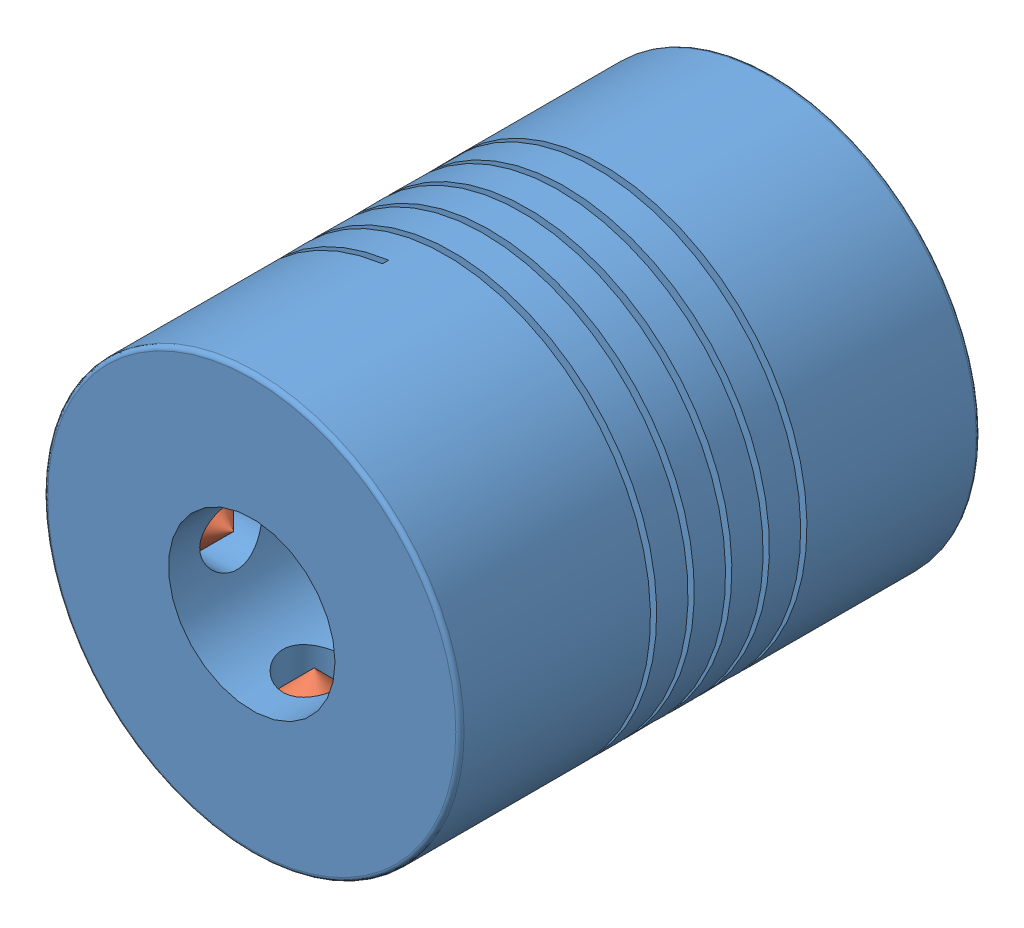
SolidWorks assembly Acople Flexible, configuration Predeterminado. Lengths in mm.
Overall size (20.77 20.77 25).
5 component instances, 2 part files, 4 mates.
Components (placement in the parent):
- Acople FlexibleSLDPRT-1: Acople FlexibleSLDPRT [Predeterminado] at (-1.3837 -0.8648 0) size (20.77 20.77 25)
- socket set screw cone point_am-7: socket set screw cone point_am [B18.3.6M - M3 x 0.5 x 6 Hex Socket Cone Pt. SS --N] at (-11.2647 -0.8648 22) x (1 0 0) z (0 -0.164849 0.986319) size (6 3 3)
- socket set screw cone point_am-8: socket set screw cone point_am [B18.3.6M - M3 x 0.5 x 6 Hex Socket Cone Pt. SS --N] at (-11.1909 -0.8648 3) x (1 0 0) z (0 0.00677 0.999977) size (6 3 3)
- socket set screw cone point_am-9: socket set screw cone point_am [B18.3.6M - M3 x 0.5 x 6 Hex Socket Cone Pt. SS --N] at (-1.3837 -10.7654 3) x (0 1 0) z (-0.345086 0 0.938571) size (6 3 3)
- socket set screw cone point_am-10: socket set screw cone point_am [B18.3.6M - M3 x 0.5 x 6 Hex Socket Cone Pt. SS --N] at (-1.3837 -10.5992 22) x (0 1 0) z (-0.865685 0 0.500588) size (6 3 3)
Mates (geometry in assembly coordinates):
- Concéntrica7: concentric anti-aligned: cylinder of Acople FlexibleSLDPRT-1 through (-161.3837 -0.8648 22) axis (1 0 0) radius 1.5; cylinder of socket set screw cone point_am-7 through (-23.9647 -0.8648 22) axis (-1 0 0) radius 1.5
- Concéntrica8: concentric anti-aligned: cylinder of Acople FlexibleSLDPRT-1 through (-161.3837 -0.8648 3) axis (1 0 0) radius 1.5; cylinder of socket set screw cone point_am-8 through (-23.8909 -0.8648 3) axis (-1 0 0) radius 1.5
- Concéntrica10: concentric anti-aligned: cylinder of Acople FlexibleSLDPRT-1 through (-1.3837 -18.8648 3) axis (0 1 0) radius 1.5; cylinder of socket set screw cone point_am-9 through (-1.3837 -23.4654 3) axis (0 -1 0) radius 1.5
- Concéntrica11: concentric anti-aligned: cylinder of Acople FlexibleSLDPRT-1 through (-1.3837 -18.8648 22) axis (0 1 0) radius 1.5; cylinder of socket set screw cone point_am-10 through (-1.3837 -23.2992 22) axis (0 -1 0) radius 1.5
